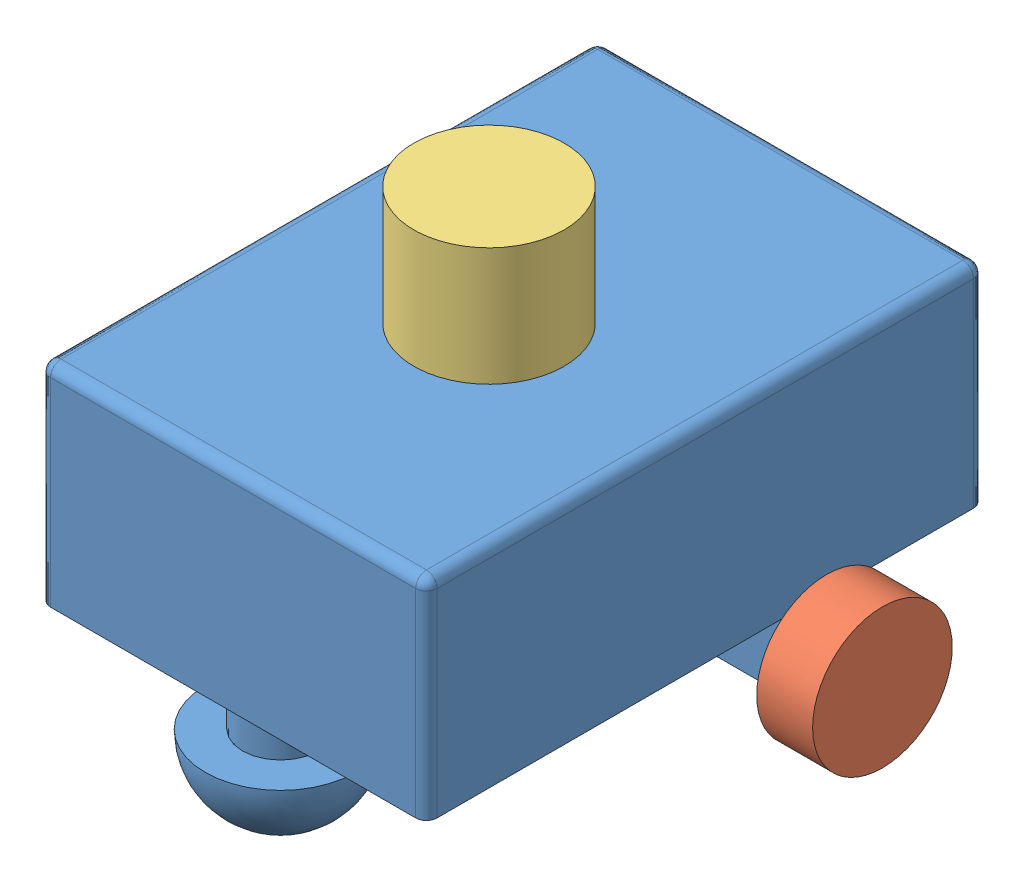
SolidWorks assembly robot_assem, configuration Default. Lengths in mm.
Overall size (260.5 205.5 272.62).
4 component instances, 3 part files, 4 mates.
Components (placement in the parent):
- robot_base-1: robot_base [Default] at (-2415.2946 -1385.4496 3766.5035) size (180 150.2 272.62)
- robot_wheel-3: robot_wheel [Default] at (-2509.7946 -1405.9496 3714.5685) x (0 0 1) z (0 -1 0) size (65 30.5 65)
- robot_wheel-4: robot_wheel [Default] at (-2320.7946 -1405.9496 3714.5685) x (0 0 -1) z (0 -1 0) size (65 30.5 65)
- rplidar_a1m12-4: rplidar_a1m12 [Default] at (-2415.2946 -1232.9496 3777.2085) x (-0.996737 0 -0.080714) z (-0.080714 0 0.996737) size (70 55 70)
Mates (geometry in assembly coordinates):
- Concentric8: concentric anti-aligned: cylinder of robot_base-1 through (-2505.2946 -1405.9496 3714.5685) axis (1 0 0) radius 5; cylinder of robot_wheel-3 through (-2505.2946 -1405.9496 3714.5685) axis (-1 0 0) radius 4
- Concentric9: concentric aligned: cylinder of robot_base-1 through (-2505.2946 -1405.9496 3714.5685) axis (1 0 0) radius 5; cylinder of robot_wheel-4 through (-2325.2946 -1405.9496 3714.5685) axis (1 0 0) radius 4
- Distance2: distance = 0 mm anti-aligned: plane of rplidar_a1m12-4 through (-2415.2946 -1287.9496 3777.2085) normal (0 -1 0); plane of robot_base-1 through (-2415.2946 -1287.9496 3766.5035) normal (0 1 0)
- Concentric14: concentric aligned: circle of robot_base-1; cylinder of rplidar_a1m12-4 through (-2415.2946 -1287.9496 3777.2085) axis (0 1 0) radius 35
